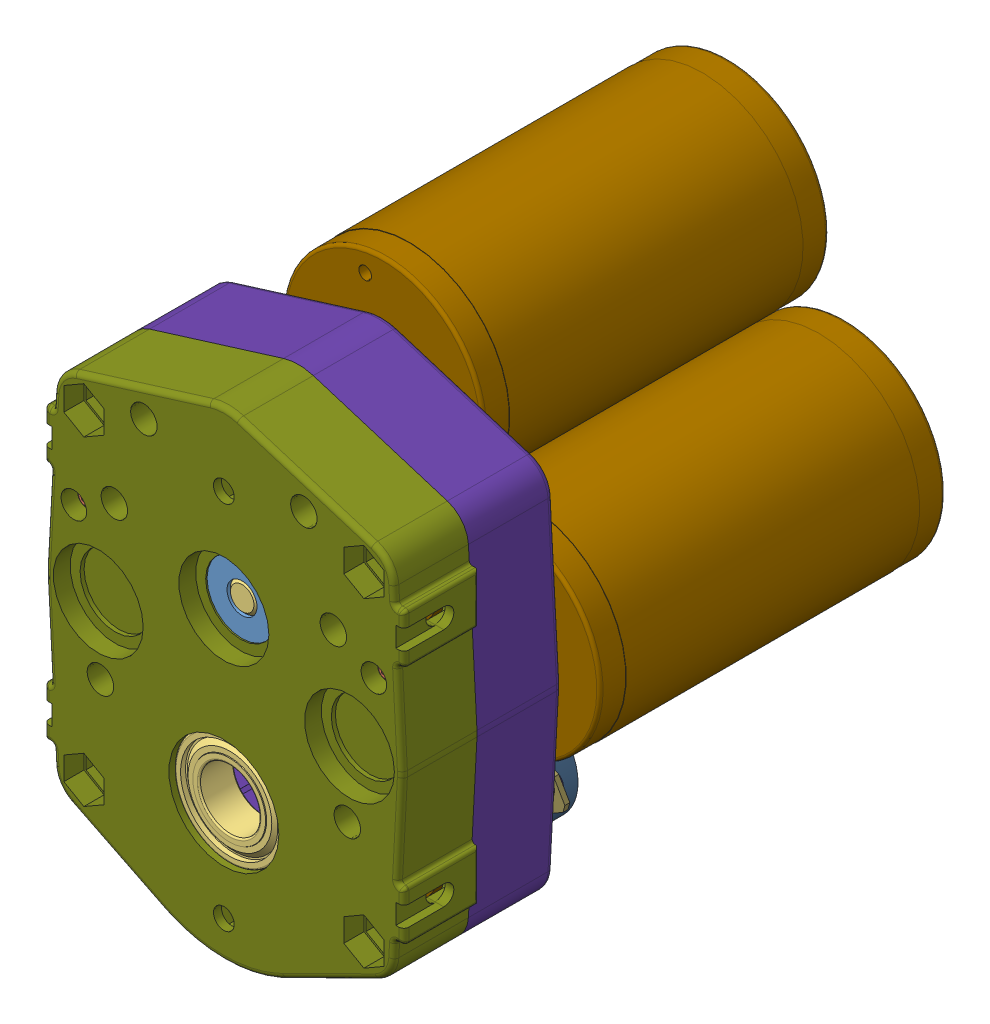
SolidWorks assembly 3 CIM Ballshifter GrayHill Encode, configuration Default. Lengths in mm.
Overall size (143.3 174.72 165.15).
58 component instances, 30 part files, 0 mates.
Components (placement in the parent):
- 217-2733-1: 217-2733 [Default] at (0 53.4162 37.6682) x (0 0 1) z (-0.00054 -1 0) size (7.11 24.61 24.61)
- 217-2733-2: 217-2733 [Default] at (0 53.4162 7.9248) x (0 0 -1) z (-0.038475 0.99926 0) size (7.11 24.61 24.61)
- 217-2731-1: 217-2731 [Default] at (0 0 -0.0127) x (1 0 0) z (0 -1 0) size (31.12 7.94 31.12)
- 217-2789-1: 217-2789 [Default] at (0 0 43.2943) x (0 0 -1) z (0.998073 -0.062043 0) size (11.1 38.4 38.4)
- 217-2428-027 Rev1_97414A630-1: 217-2428-027 Rev1_97414A630 [Default] at (0 0 -7.0307) x (0 0 1) z (0.453751 0.891129 0) size (0.64 5.89 7.9)
- 217-2788_57155K375-1: 217-2788_57155K375 [Default] at (0 0 -8.9357) x (0.971787 -0.235861 0) z (0 0 1) size (9.53 9.53 3.17)
- 217-2428-012 Rev3-1: 217-2428-012 Rev3 [Default] at (0 0 -40.386) size (63.5 22.23 2.29)
- 217-2428-027 Rev1_97414A630-2: 217-2428-027 Rev1_97414A630 [Default] at (0 0 -10.8407) x (0 0 1) z (-0.054891 -0.998492 0) size (0.64 5.89 7.9)
- 217-2428-005 Rev1-1: 217-2428-005 Rev1 [Default] at (25.4 0 -19.05) x (-0.557362 -0.83027 0) z (-0.83027 0.557362 0) size (7.33 38.98 6.35)
- 217-2428-005 Rev1-2: 217-2428-005 Rev1 [Default] at (-25.4 0 -19.05) x (0.667436 0.744667 0) z (0.744667 -0.667436 0) size (7.33 38.98 6.35)
- SCREW-832-0375-1: SCREW-832-0375 [Default] at (25.4 0 -42.5958) x (0 0 1) z (-0.875404 0.483392 0) size (11.73 7.92 7.92)
- SCREW-832-0375-2: SCREW-832-0375 [Default] at (-25.4 0 -42.5958) x (0 0 1) z (-0.966319 0.257347 0) size (11.73 7.92 7.92)
- SCREW-832-0375-3: SCREW-832-0375 [Default] at (25.4 0 5.3848) x (0 0 -1) z (1 0 0) size (11.73 7.92 7.92)
- SCREW-832-0375-4: SCREW-832-0375 [Default] at (-25.4 0 5.3848) x (0 0 -1) z (0.941463 -0.337115 0) size (11.73 7.92 7.92)
- SBS1_SBS-0632-0250-1: SBS1_SBS-0632-0250 [Default] at (15.494 0 -36.2458) x (0 0 -1) z (0.854303 -0.519775 0) size (8.57 6.68 6.65)
- SBS1_SBS-0632-0250-2: SBS1_SBS-0632-0250 [Default] at (-15.494 0 -36.2458) x (0 0 -1) z (0.854303 -0.519775 0) size (8.57 6.68 6.65)
- 217-2428-017 Rev2-1: 217-2428-017 Rev2 [Default] at (12.7 -21.997 -3.6517) x (-0.578458 -0.815712 0) z (0 0 -1) size (14.73 14.73 7.37)
- 217-2428-016 Rev2_Spur01-1: 217-2428-016 Rev2_Spur01 [Default] at (0 0 -3.6517) x (0.918689 -0.394983 0) z (0 0 1) size (40.67 40.74 13.3)
- 217-2428-019 Rev1-1: 217-2428-019 Rev1 [Default] at (12.7 -21.997 -20.6248) x (0.866025 0.5 0) z (0 0 1) size (50.8 19.05 1.57)
- 217-2428-006 Rev1-1: 217-2428-006 Rev1 [Default] at (32.079 -14.2875 -9.525) x (-0.95139 -0.30799 0) z (-0.30799 0.95139 0) size (7.33 19.93 6.35)
- 217-2428-006 Rev1-2: 217-2428-006 Rev1 [Default] at (-3.6662 -34.925 -9.525) x (-0.486716 0.87356 0) z (0.87356 0.486716 0) size (7.33 19.93 6.35)
- SCREW-832-0375-5: SCREW-832-0375 [Default] at (32.079 -14.2875 4.7498) x (0 0 -1) z (0.980613 0.195955 0) size (11.73 7.92 7.92)
- SCREW-832-0375-6: SCREW-832-0375 [Default] at (-3.6662 -34.925 5.3848) x (0 0 -1) z (-0.826375 -0.56312 0) size (11.73 7.92 7.92)
- SCREW-832-0375-7: SCREW-832-0375 [Default] at (-3.6662 -34.925 -22.8346) x (0 0 1) z (0.948865 0.315681 0) size (11.73 7.92 7.92)
- SCREW-832-0375-8: SCREW-832-0375 [Default] at (32.079 -14.2875 -22.8346) x (0 0 1) z (-0.875404 0.483392 0) size (11.73 7.92 7.92)
- 217-2614-001_12t-1: 217-2614-001_12t [Default] at (36.9798 39.6868 15.8623) x (0.996195 0.087156 0) z (0 0 1) size (18.29 18.29 19)
- 217-2761-001 rev1-1: 217-2761-001 rev1 [Default] at (36.6486 43.4723 16.1) x (-0.996195 -0.087156 0) z (0 0 1) size (2 2 20)
- 217-2761-001 rev1-2: 217-2761-001 rev1 [Default] at (-36.6486 43.4723 16.1) x (0.996195 -0.087156 0) z (0 0 1) size (2 2 20)
- 217-2614-001_12t-2: 217-2614-001_12t [Default] at (-36.9798 39.6868 15.8623) x (0.996195 -0.087156 0) z (0 0 1) size (18.29 18.29 19)
- 217-2614-001_12t-3: 217-2614-001_12t [Default] at (0 92.8624 15.8623) x (0.97459 0.223996 0) z (0 0 1) size (18.29 18.29 19)
- 217-2761-001 rev1-3: 217-2761-001 rev1 [Default] at (-0.8512 96.5658 16.1) x (0.97459 0.223996 0) z (0 0 1) size (2 2 20)
- 217-3195-002 rev1-1: 217-3195-002 rev1 [Default] at (0 0 50.546) x (-1 0 0) z (0 0 -1) size (114.31 152.24 24.96)
- 217-3195-001 Rev1-1: 217-3195-001 Rev1 [Default] at origin size (113.41 152.24 26.86)
- Nylock Nut_NNY2520-ZC-1: Nylock Nut_NNY2520-ZC [Default] at (48.8823 73.025 37.846) x (0 0.866025 -0.5) z (-1 0 0) size (12.85 11.89 7.62)
- Nylock Nut_NNY2520-ZC-2: Nylock Nut_NNY2520-ZC [Default] at (48.8823 -3.175 37.846) x (0 0 -1) z (-1 0 0) size (12.85 11.89 7.62)
- Nylock Nut_NNY2520-ZC-3: Nylock Nut_NNY2520-ZC [Default] at (44.45 85.725 7.8613) x (0 1 0) z (0 0 -1) size (12.85 11.89 7.62)
- NUT-832-NYLOCK-1: NUT-832-NYLOCK [Default] at (47.625 58.1787 5.3937) x (0.5 0.866025 0) z (-0.866025 0.5 0) size (10.2 5.86 8.12)
- NUT-832-NYLOCK-2: NUT-832-NYLOCK [Default] at (-47.625 58.1787 5.3937) x (-1 0 0) z (0 -1 0) size (10.2 5.86 8.12)
- SCREW-832-1750-1: SCREW-832-1750 [Default] at (-47.625 58.1787 47.0408) x (0 0 -1) z (-0.960822 -0.277167 0) size (46.66 7.92 7.92)
- SCREW-832-1750-2: SCREW-832-1750 [Default] at (47.625 58.1787 47.0408) x (0 0 -1) z (-0.960822 -0.277167 0) size (46.66 7.92 7.92)
- Nylock Nut_NNY2520-ZC-4: Nylock Nut_NNY2520-ZC [Default] at (44.45 -15.875 7.8613) x (0 1 0) z (0 0 -1) size (12.85 11.89 7.62)
- 217-2428-004 Rev3-1: 217-2428-004 Rev3 [Default] at (0 53.4162 22.7711) x (0.360537 -0.932745 0) z (0 0 1) size (11 9.53 43.92)
- Nylock Nut_NNY2520-ZC-5: Nylock Nut_NNY2520-ZC [Default] at (-44.45 85.725 7.8613) x (0 1 0) z (0 0 -1) size (12.85 11.89 7.62)
- Nylock Nut_NNY2520-ZC-6: Nylock Nut_NNY2520-ZC [Default] at (-44.45 -15.875 7.8613) x (-0.866025 0.5 0) z (0 0 -1) size (12.85 11.89 7.62)
- SBS1_SBS-2520-1625SS-1: SBS1_SBS-2520-1625SS [Default] at (44.45 85.725 42.4688) x (0 0 -1) z (-0.251219 0.96793 0) size (45.3 11.22 11.17)
- SBS1_SBS-2520-1625SS-2: SBS1_SBS-2520-1625SS [Default] at (-44.45 85.725 42.4688) x (0 0 -1) z (-0.251219 0.96793 0) size (45.3 11.22 11.17)
- SBS1_SBS-2520-1625SS-3: SBS1_SBS-2520-1625SS [Default] at (-44.45 -15.875 42.4688) x (0 0 -1) z (-0.251219 0.96793 0) size (45.3 11.22 11.17)
- SBS1_SBS-2520-1625SS-4: SBS1_SBS-2520-1625SS [Default] at (44.45 -15.875 42.4688) x (0 0 -1) z (-0.251219 0.96793 0) size (45.3 11.22 11.17)
- 217-2428-021 Rev1-1: 217-2428-021 Rev1 [Default] at (0 53.4162 9.5123) x (0.451333 -0.892356 0) z (0 0 1) size (15.88 15.88 3.17)
- 217-2428-029 Rev1-1: 217-2428-029 Rev1 [Default] at (0 53.4162 36.957) x (0.999846 0.017557 0) z (0 0 1) size (15.88 15.88 1.12)
- Grayhill Lock Washer-1: Grayhill Lock Washer [Default] at (12.7 -21.997 -18.6817) x (1 0 0) z (0 0 1) size (19.69 19.69 0.74)
- Grayhill Nut-1: Grayhill Nut [Default] at (12.7 -21.997 -17.0434) x (1 0 0) z (0 0 1) size (18.33 15.88 2.54)
- 217-2000-1: 217-2000 [Default] at (0 92.8624 0) x (0 0 -1) z (0.97459 0.223996 0) size (150.2 64.01 64.01)
- 217-2000-2: 217-2000 [Default] at (-36.9798 39.6868 0) x (0 0 -1) z (0.996195 -0.087156 0) size (150.2 64.01 64.01)
- 217-2000-3: 217-2000 [Default] at (36.9798 39.6868 0) x (0 0 -1) z (0.996195 0.087156 0) size (150.2 64.01 64.01)
- Grahill Encoder-1: Grahill Encoder [Default] at (12.7 -21.997 -16.1798) x (0.968646 -0.248444 0) z (0.248444 0.968646 0) size (31.75 31.12 31.75)
- 217-2711-001_50t-1: 217-2711-001_50t [Default] at (0 53.4162 17.4244) x (0.154138 0.988049 0) z (0 0 1) size (66.7 66.76 12.65)
- 217-3210-001 Rev1_30t-1: 217-3210-001 Rev1_30t [Default] at (0 53.4162 30.0736) x (0.778607 -0.627512 0) z (0 0 1) size (41.01 41.12 12.65)
